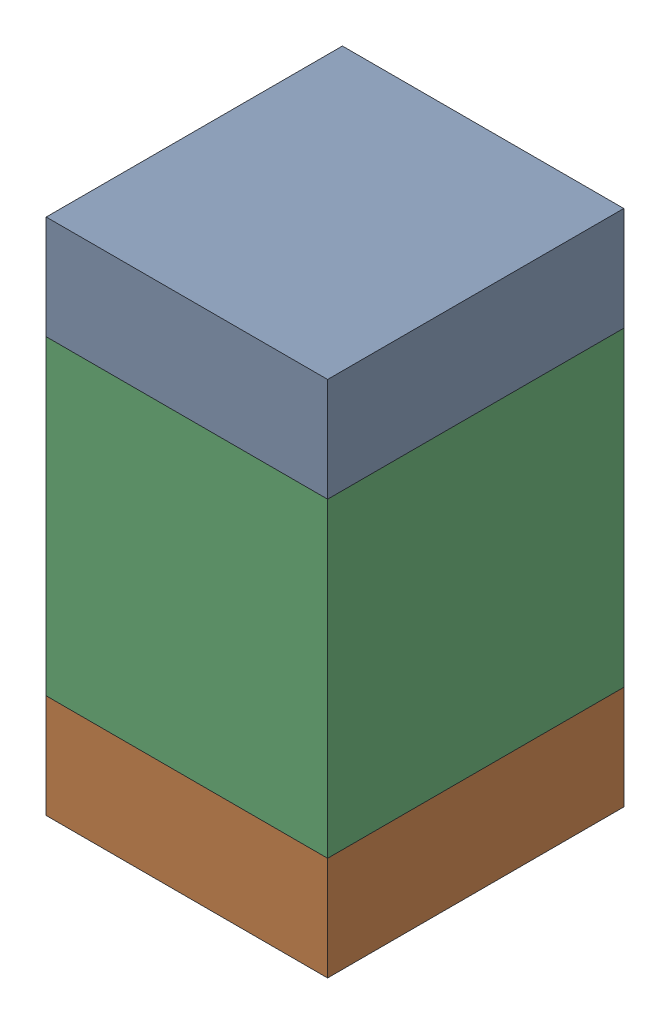
SolidWorks assembly C428PCB, configuration Default. Lengths in mm.
Overall size (0.95 1.75 1).
6 component instances, 2 part files, 0 mates.
Components (placement in the parent):
- 761616520-1: 761616520 [Default] at (89.8 89.6 -2.6638) size (0.95 0.35 1)
  - Extruded_6-1: Extruded_6 [Default] at origin size (0.95 0.35 1)
- 761616520-2: 761616520 [Default] at (89.8 88.2 -2.6638) size (0.95 0.35 1)
  - Extruded_6-1: Extruded_6 [Default] at origin size (0.95 0.35 1)
- 761616384-1: 761616384 [Default] at (89.8 88.9 -2.6638) size (0.95 1.05 1)
  - Extruded_5-1: Extruded_5 [Default] at origin size (0.95 1.05 1)
